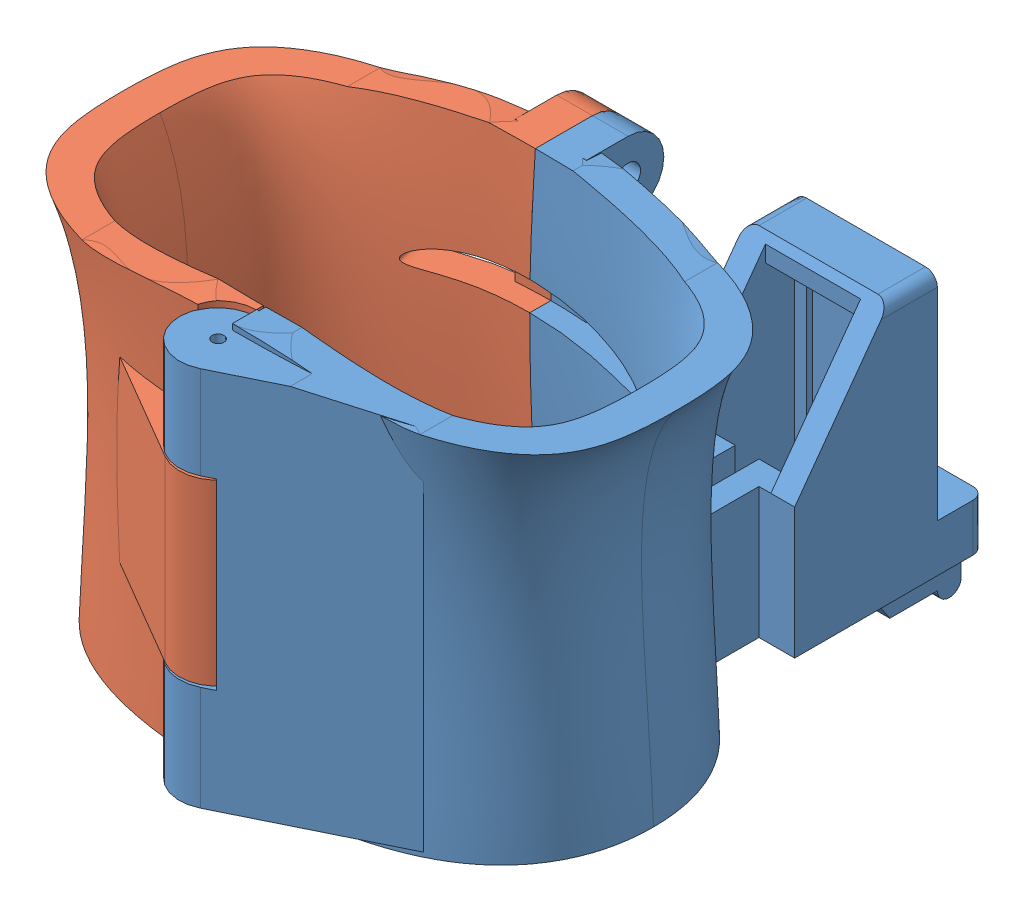
SolidWorks assembly Telemed-MicrUs-L12-SensorHolder, configuration Default. Lengths in mm.
Overall size (58.34 35.26 48.72).
2 component instances, 2 part files, 3 mates.
Components (placement in the parent):
- TelemedHolder_L12_MarkedSide-1: TelemedHolder_L12_MarkedSide [Default] at (21.6381 69.5691 31.4061) size (32.42 35.25 48.72)
- TelemedHolder-L12_UnmarkedSide-1: TelemedHolder-L12_UnmarkedSide [Default] at (21.6381 69.5691 31.4065) size (32.42 35.26 37.72)
Mates (geometry in assembly coordinates):
- Coincident1: coincident anti-aligned: plane of TelemedHolder_L12_MarkedSide-1 through (21.6381 15.6372 17.523) normal (-1 0 0); plane of TelemedHolder-L12_UnmarkedSide-1 through (21.6381 15.5165 20.1206) normal (1 0 0)
- Coincident2: coincident aligned: plane of TelemedHolder_L12_MarkedSide-1 through (24.6381 33.0838 15.1709) normal (0 0 -1); plane of TelemedHolder-L12_UnmarkedSide-1 through (18.6381 33.0838 15.1709) normal (0 0 -1)
- Coincident3: coincident aligned: plane of TelemedHolder_L12_MarkedSide-1 through (21.6381 6.0838 15.4822) normal (0 -1 0); plane of TelemedHolder-L12_UnmarkedSide-1 through (21.6381 6.0838 15.4826) normal (0 -1 0)
